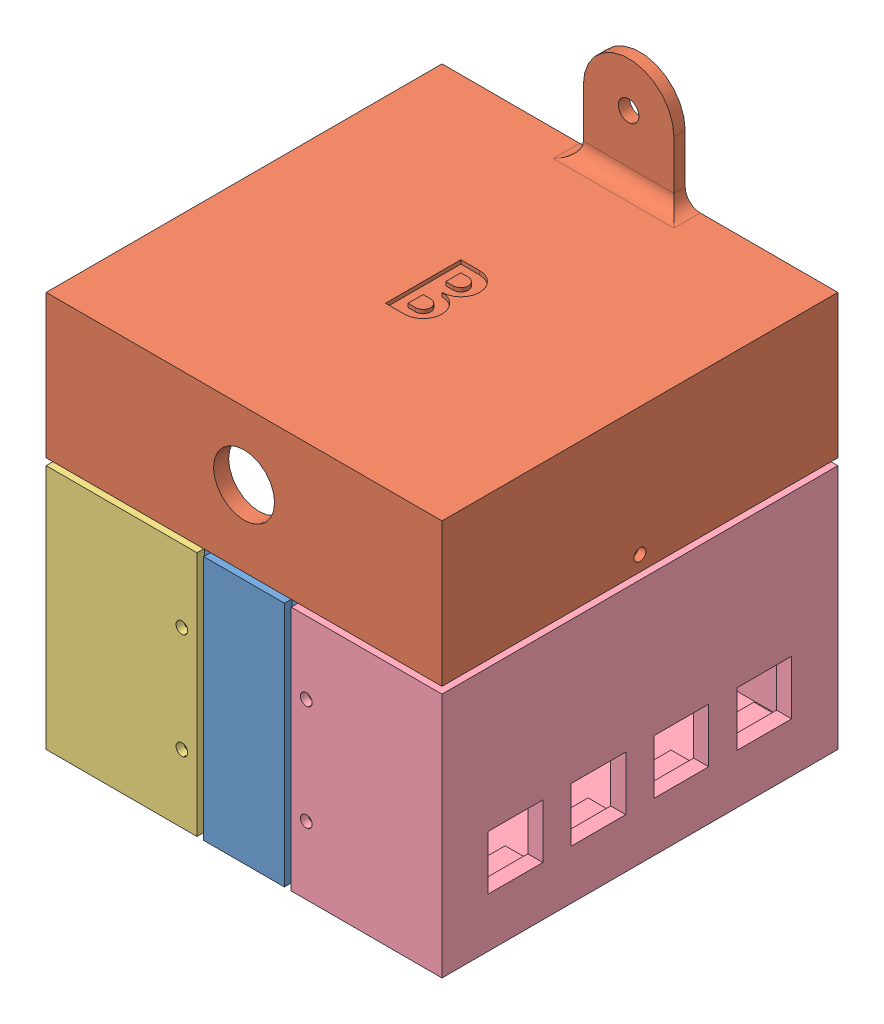
SolidWorks assembly 1.1box, configuration Default. Lengths in mm.
Overall size (105 134 105).
4 component instances, 4 part files, 3 mates.
Components (placement in the parent):
- 1.1middle-1: 1.1middle [Default] at (38.2006 1.641 59.8275) size (41 75 105)
- 1.1top-2: 1.1top [Default] at (38.2006 104.641 59.8275) x (-1 0 0) z (0 0 1) size (105 67 105)
- 1.10lx-1: 1.10lx [Default] at (-5.9564 -17.3468 -35.5082) size (40 75 105)
- 1.10rx-1: 1.10rx [Default] at (95.0053 -27.2942 167.208) x (-1 0 0) z (0 0 -1) size (40 75 105)
Mates (geometry in assembly coordinates):
- Coincident1: coincident: point of 1.1middle-1; point of 1.10lx-1
- Coincident3: coincident: point of 1.1middle-1; point of 1.10rx-1
- Coincident4: coincident: point of 1.1top-2; point of 1.10rx-1
